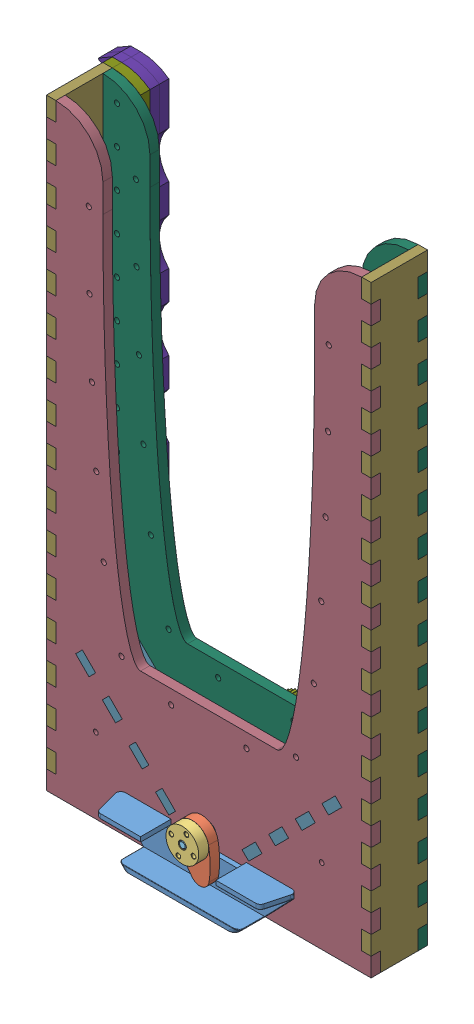
SolidWorks assembly Goal Lift Assembly, configuration Default. Lengths in mm.
Overall size (228.41 406.4 102.81).
27 component instances, 17 part files, 48 mates.
Components (placement in the parent):
- Goal Lift Claw-1: Goal Lift Claw [Default] at (162.1083 92.921 445.1283) size (118.72 25.4 20.64)
- Goal Lift Cam-1: Goal Lift Cam [Default] at (222.4333 124.671 430.8033) x (-0.964839 -0.26284 0) z (0 0 -1) size (22.23 36.51 6.35)
- Tetrix Axle Hub-1: Tetrix Axle Hub [Default] at (222.4333 124.671 430.8033) x (0.941793 -0.336194 0) z (0 0 -1) size (22.1 22.1 9.5)
  - Tetrix Axle Hub Body-1: Tetrix Axle Hub Body [Default] at origin size (22.1 22.1 9.5)
  - Tetrix Axle Hub Set Screw-1: Tetrix Axle Hub Set Screw [Default] at (6.9308 6.9308 -3.325) x (-0.707107 0.707107 0) z (0 0 1) size (4.83 7.94 4.83)
- Tetrix Axle 100mm-1: Tetrix Axle 100mm [Default] at (222.4333 124.671 387.5533) x (1 0 0) z (0 -1 0) size (4.7 100 4.22)
- Tetrix Bushing Bronze-1: Tetrix Bushing Bronze [Default] at (222.4333 124.671 421.3283) x (1 0 0) z (0 1 0) size (9.56 12.71 9.56)
- Tetrix Bushing Bronze-2: Tetrix Bushing Bronze [Default] at (222.4333 124.671 380.0283) x (1 0 0) z (0 -1 0) size (9.56 12.71 9.56)
- Tetrix Axle Hub-2: Tetrix Axle Hub [Default] at (222.4333 124.671 362.1283) x (-0.923728 -0.383049 0) z (0 0 -1) size (22.1 22.1 9.5)
  - Tetrix Axle Hub Body-1: Tetrix Axle Hub Body [Default] at origin size (22.1 22.1 9.5)
  - Tetrix Axle Hub Set Screw-1: Tetrix Axle Hub Set Screw [Default] at (6.9308 6.9308 -3.325) x (-0.707107 0.707107 0) z (0 0 1) size (4.83 7.94 4.83)
- Tetrix Gear 40T-1: Tetrix Gear 40T [Default] at (222.4333 156.671 355.9283) x (0 0 1) z (0.399864 -0.916575 0) size (6.2 33.53 33.53)
- Tetrix Axle Spacer Small-1: Tetrix Axle Spacer Small [Default] at (222.4333 124.671 422.8908) x (-0.923728 -0.383049 0) z (0 0 -1) size (9.5 9.5 3.12)
- Tetrix Servo 180° (with Horn)-1: Tetrix Servo 180° (with Horn) [Default] at (217.4823 175.796 382.3552) x (0 -1 0) z (1 0 0) size (22 47.52 56.6)
  - Tetrix Servo Body Screw B-1: Tetrix Servo Body Screw B [Default] at (19.125 20.2268 4.9509) size (5.08 10.95 5.08)
  - Tetrix Servo Body B-1: Tetrix Servo Body B [Default] at (19.125 0.7268 4.9509) size (20 43.2 56.6)
  - Tetrix Servo Horn B-1: Tetrix Servo Horn B [Default] at (19.125 18.2268 4.9509) size (22 6.2 22)
- Tetrix Gear 40T-2: Tetrix Gear 40T [Default] at (222.4333 124.671 355.9283) x (0 0 1) z (-0.994228 -0.107291 0) size (6.2 33.53 33.53)
- Goal Lift Side-1: Goal Lift Side [Default] at (325.6208 92.921 419.7283) size (6.35 406.4 38.1)
- Goal Lift Side-2: Goal Lift Side [Default] at (112.8958 92.921 419.7283) size (6.35 406.4 38.1)
- Goal Lift Back-2: Goal Lift Back [Default] at (112.8958 92.921 413.3783) size (219.07 406.4 6.35)
- Goal Lift Support-1: Goal Lift Support [Default] at (222.4333 92.921 381.6283) x (0 0 1) z (-0.707107 0.707107 0) size (38.1 127 6.35)
- Goal Lift Support-2: Goal Lift Support [Default] at (222.4333 92.921 419.7283) x (0 0 -1) z (0.707107 0.707107 0) size (38.1 127 6.35)
- Goal Lift Front-1: Goal Lift Front [Default] at (112.8958 92.921 381.6283) size (219.07 406.4 6.35)
- Goal Lift Spacer-1: Goal Lift Spacer [Default] at (112.8958 223.096 381.6283) x (-1 0 0) z (0 0 -1) size (25.4 276.23 6.35)
- Goal Lift Rack-1: Goal Lift Rack [Default] at (112.8958 223.096 368.9283) x (-1 0 0) z (0 0 -1) size (34.73 276.23 6.35)
- Goal Lift Rack-2: Goal Lift Rack [Default] at (112.8958 223.096 375.2783) x (-1 0 0) z (0 0 -1) size (34.73 276.23 6.35)
Mates (geometry in assembly coordinates):
- Concentric3: concentric anti-aligned: cylinder of Tetrix Axle 100mm-1 through (222.4333 124.671 437.5533) axis (0 0 1) radius 2.35; cylinder of Tetrix Bushing Bronze-2 through (222.4333 124.671 380.0283) axis (0 0 -1) radius 2.375
- Coincident8: coincident anti-aligned: plane of Goal Lift Cam-1 through (199.1965 110.6283 430.8033) normal (0 0 1); plane of Tetrix Axle Hub-1/Tetrix Axle Hub Body-1 through (222.4333 124.671 430.8033) normal (0 0 -1)
- Concentric4: concentric anti-aligned: cylinder of Goal Lift Cam-1 through (222.4333 124.671 424.4533) axis (0 0 1) radius 4; cylinder of Tetrix Axle Hub-1/Tetrix Axle Hub Body-1 through (222.4333 124.671 430.8033) axis (0 0 -1) radius 11.05
- Concentric6: concentric anti-aligned: cylinder of Tetrix Axle Hub-1/Tetrix Axle Hub Body-1 through (222.4333 124.671 430.8033) axis (0 0 -1) radius 11.05; cylinder of Tetrix Axle 100mm-1 through (222.4333 124.671 437.5533) axis (0 0 1) radius 2.35
- Coincident9: coincident anti-aligned: plane of Tetrix Bushing Bronze-1 through (217.6533 124.671 421.3283) normal (0 0 1); plane of Tetrix Axle Spacer Small-1 through (222.4333 124.671 421.3283) normal (0 0 -1)
- Concentric7: concentric anti-aligned: cylinder of Tetrix Axle 100mm-1 through (222.4333 124.671 437.5533) axis (0 0 1) radius 2.35; cylinder of Tetrix Axle Spacer Small-1 through (222.4333 124.671 424.4533) axis (0 0 -1) radius 4.75
- Coincident10: coincident anti-aligned: plane of Goal Lift Cam-1 through (199.1965 110.6283 424.4533) normal (0 0 -1); plane of Tetrix Axle Spacer Small-1 through (222.4333 124.671 424.4533) normal (0 0 1)
- Coincident11: coincident aligned: plane of Tetrix Axle Hub-1/Tetrix Axle Hub Body-1 through (222.4333 124.671 437.5533) normal (0 0 1); plane of Tetrix Axle 100mm-1 through (220.5833 124.671 437.5533) normal (0 0 1)
- Concentric8: concentric anti-aligned: cylinder of Tetrix Axle 100mm-1 through (222.4333 124.671 437.5533) axis (0 0 1) radius 2.35; cylinder of Tetrix Axle Hub-2/Tetrix Axle Hub Body-1 through (222.4333 124.671 362.1283) axis (0 0 -1) radius 11.05
- Coincident13: coincident anti-aligned: plane of Tetrix Gear 40T-1 through (222.4333 156.671 362.1283) normal (0 0 1); plane of Tetrix Servo 180° (with Horn)-1/Tetrix Servo Horn B-1 through (222.4333 156.671 362.1283) normal (0 0 -1)
- Concentric9: concentric aligned: cylinder of Tetrix Gear 40T-1 through (222.4333 156.671 405.9284) axis (0 0 -1) radius 4; cylinder of Tetrix Servo 180° (with Horn)-1/Tetrix Servo Horn B-1 through (222.4333 156.671 362.1283) axis (0 0 -1) radius 4.4
- Coincident14: coincident anti-aligned: plane of Tetrix Axle Hub-2/Tetrix Axle Hub Body-1 through (222.4333 124.671 362.1283) normal (0 0 -1); plane of Tetrix Gear 40T-2 through (222.4333 124.671 362.1283) normal (0 0 1)
- Concentric10: concentric aligned: cylinder of Tetrix Axle Hub-2/Tetrix Axle Hub Body-1 through (222.4333 124.671 362.1283) axis (0 0 -1) radius 11.05; cylinder of Tetrix Gear 40T-2 through (222.4333 124.671 405.9284) axis (0 0 -1) radius 4
- Coincident15: coincident aligned: plane of Tetrix Gear 40T-1 through (222.4333 156.671 355.9283) normal (0 0 -1); plane of Tetrix Gear 40T-2 through (222.4333 124.671 355.9283) normal (0 0 -1)
- Coincident32: coincident aligned: plane of Goal Lift Side-1 through (331.9708 499.321 419.7283) normal (0 1 0); plane of Goal Lift Side-2 through (119.2458 499.321 419.7283) normal (0 1 0)
- Coincident36: coincident aligned: plane of Goal Lift Side-2 through (119.2458 92.921 419.7283) normal (0 0 1); plane of Goal Lift Back-2 through (112.8958 92.921 419.7283) normal (0 0 1)
- Coincident37: coincident aligned: plane of Goal Lift Side-2 through (112.8958 92.921 419.7283) normal (-1 0 0); plane of Goal Lift Back-2 through (112.8958 499.321 419.7283) normal (-1 0 0)
- Coincident39: coincident anti-aligned: plane of Tetrix Bushing Bronze-1 through (218.4333 124.671 419.7283) normal (0 0 -1); plane of Goal Lift Back-2 through (112.8958 92.921 419.7283) normal (0 0 1)
- Coincident41: coincident aligned: plane of Goal Lift Back-2 through (112.8958 92.921 419.7283) normal (0 0 1); plane of Goal Lift Support-1 through (217.9431 97.4112 419.7283) normal (0 0 1)
- Coincident42: coincident anti-aligned: plane of Goal Lift Back-2 through (294.2753 164.7631 419.7283) normal (-0.707107 0.707107 0); plane of Goal Lift Support-1 through (222.4333 92.921 381.6283) normal (0.707107 -0.707107 0)
- Coincident43: coincident anti-aligned: plane of Goal Lift Back-2 through (312.2358 182.7236 419.7283) normal (-0.707107 -0.707107 0); plane of Goal Lift Support-1 through (307.7457 187.2137 381.6283) normal (0.707107 0.707107 0)
- Coincident44: coincident anti-aligned: plane of Goal Lift Back-2 through (155.0813 169.2532 419.7283) normal (-0.707107 -0.707107 0); plane of Goal Lift Support-2 through (226.9234 97.4112 419.7283) normal (0.707107 0.707107 0)
- Coincident45: coincident aligned: plane of Goal Lift Back-2 through (112.8958 92.921 419.7283) normal (0 0 1); plane of Goal Lift Support-2 through (226.9234 97.4112 419.7283) normal (0 0 1)
- Coincident46: coincident anti-aligned: plane of Goal Lift Back-2 through (132.6307 182.7236 419.7283) normal (0.707107 -0.707107 0); plane of Goal Lift Support-2 through (137.1208 187.2137 419.7283) normal (-0.707107 0.707107 0)
- Coincident47: coincident aligned: plane of Goal Lift Side-1 through (331.9708 92.921 381.6283) normal (0 0 -1); plane of Goal Lift Front-1 through (112.8958 92.921 381.6283) normal (0 0 -1)
- Coincident48: coincident aligned: plane of Goal Lift Side-1 through (331.9708 92.921 419.7283) normal (1 0 0); plane of Goal Lift Front-1 through (331.9708 92.921 387.9783) normal (1 0 0)
- Coincident49: coincident aligned: plane of Goal Lift Side-1 through (331.9708 92.921 419.7283) normal (0 -1 0); plane of Goal Lift Front-1 through (112.8958 92.921 387.9783) normal (0 -1 0)
- Coincident50: coincident aligned: plane of Goal Lift Side-1 through (331.9708 92.921 419.7283) normal (1 0 0); plane of Goal Lift Back-2 through (331.9708 92.921 419.7283) normal (1 0 0)
- Coincident51: coincident aligned: plane of Goal Lift Side-1 through (331.9708 92.921 419.7283) normal (0 0 1); plane of Goal Lift Back-2 through (112.8958 92.921 419.7283) normal (0 0 1)
- Coincident52: coincident aligned: plane of Goal Lift Side-1 through (331.9708 92.921 419.7283) normal (0 -1 0); plane of Goal Lift Back-2 through (112.8958 92.921 419.7283) normal (0 -1 0)
- Coincident53: coincident anti-aligned: plane of Tetrix Servo 180° (with Horn)-1/Tetrix Servo Body B-1 through (187.3333 148.796 381.6283) normal (0 0 1); plane of Goal Lift Front-1 through (112.8958 92.921 381.6283) normal (0 0 -1)
- Concentric11: concentric aligned: cylinder of Tetrix Servo 180° (with Horn)-1/Tetrix Servo Body B-1 through (188.4333 161.671 379.1283) axis (0 0 1) radius 2.15; cylinder of Goal Lift Front-1 through (188.4333 161.671 381.6283) axis (0 0 1) radius 1
- Concentric12: concentric aligned: cylinder of Tetrix Servo 180° (with Horn)-1/Tetrix Servo Body B-1 through (188.4333 151.671 379.1283) axis (0 0 1) radius 2.15; cylinder of Goal Lift Front-1 through (188.4333 151.671 381.6283) axis (0 0 1) radius 1
- Coincident54: coincident anti-aligned: plane of Tetrix Bushing Bronze-2 through (218.4333 124.671 381.6283) normal (0 0 1); plane of Goal Lift Front-1 through (112.8958 92.921 381.6283) normal (0 0 -1)
- Concentric13: concentric anti-aligned: cylinder of Tetrix Bushing Bronze-2 through (222.4333 124.671 380.0283) axis (0 0 -1) radius 4; cylinder of Goal Lift Front-1 through (222.4333 124.671 381.6283) axis (0 0 1) radius 3.9688
- Coincident55: coincident aligned: plane of Goal Lift Claw-1 through (282.7583 92.921 445.1283) normal (0 -1 0); plane of Goal Lift Back-2 through (112.8958 92.921 419.7283) normal (0 -1 0)
- Coincident57: coincident anti-aligned: plane of Goal Lift Claw-1 through (282.7583 92.921 419.7283) normal (0 0 -1); plane of Goal Lift Back-2 through (112.8958 92.921 419.7283) normal (0 0 1)
- Concentric14: concentric aligned: cylinder of Goal Lift Claw-1 through (260.5333 105.621 419.7283) axis (0 0 1) radius 1.75; cylinder of Goal Lift Back-2 through (260.5333 105.621 413.3783) axis (0 0 1) radius 1.5875
- Concentric15: concentric aligned: cylinder of Tetrix Bushing Bronze-1 through (222.4333 124.671 421.3283) axis (0 0 1) radius 4; cylinder of Goal Lift Back-2 through (222.4333 124.671 413.3783) axis (0 0 1) radius 3.9688
- Coincident58: coincident anti-aligned: plane of Goal Lift Front-1 through (112.8958 92.921 381.6283) normal (0 0 -1); plane of Goal Lift Spacer-1 through (112.8958 223.096 381.6283) normal (0 0 1)
- Coincident59: coincident aligned: plane of Goal Lift Side-2 through (112.8958 92.921 419.7283) normal (-1 0 0); plane of Goal Lift Spacer-1 through (112.8958 223.096 375.2783) normal (-1 0 0)
- Coincident60: coincident aligned: plane of Goal Lift Side-2 through (119.2458 499.321 419.7283) normal (0 1 0); plane of Goal Lift Spacer-1 through (112.8958 499.321 375.2783) normal (0 1 0)
- Coincident61: coincident anti-aligned: plane of Goal Lift Rack-1 through (112.8958 223.096 368.9283) normal (0 0 1); plane of Goal Lift Rack-2 through (112.8958 223.096 368.9283) normal (0 0 -1)
- Coincident62: coincident aligned: plane of Goal Lift Rack-1 through (112.8958 223.096 362.5783) normal (-1 0 0); plane of Goal Lift Rack-2 through (112.8958 223.096 368.9283) normal (-1 0 0)
- Coincident63: coincident aligned: plane of Goal Lift Rack-1 through (112.8958 499.321 362.5783) normal (0 1 0); plane of Goal Lift Rack-2 through (112.8958 499.321 368.9283) normal (0 1 0)
- Coincident64: coincident aligned: plane of Goal Lift Spacer-1 through (112.8958 223.096 375.2783) normal (-1 0 0); plane of Goal Lift Rack-1 through (112.8958 223.096 362.5783) normal (-1 0 0)
- Coincident65: coincident anti-aligned: plane of Goal Lift Spacer-1 through (112.8958 223.096 375.2783) normal (0 0 -1); plane of Goal Lift Rack-2 through (112.8958 223.096 375.2783) normal (0 0 1)
- Coincident66: coincident aligned: plane of Goal Lift Side-2 through (119.2458 499.321 419.7283) normal (0 1 0); plane of Goal Lift Rack-2 through (112.8958 499.321 368.9283) normal (0 1 0)
